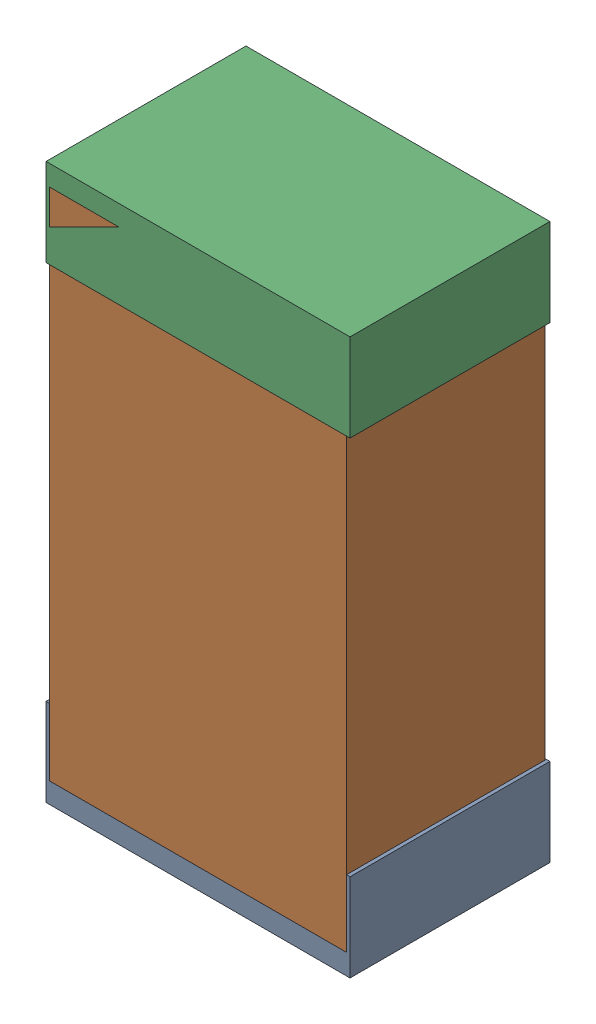
SolidWorks assembly R47Kanaloa_v2.0.0_Motor, configuration Default. Lengths in mm.
Overall size (1.3 2.38 0.85).
6 component instances, 2 part files, 0 mates.
Components (placement in the parent):
- 330415056-1: 330415056 [Default] at (53.34 149.368 -1.9574) size (1.3 0.38 0.85)
  - Extruded_2-1: Extruded_2 [Default] at origin size (1.3 0.38 0.85)
- 334787376-1: 334787376 [Default] at (53.34 150.368 -1.9524) size (1.27 2.2 0.85)
  - Extruded_16-1: Extruded_16 [Default] at origin size (1.27 2.2 0.85)
- 330415056-2: 330415056 [Default] at (53.34 151.368 -1.9574) size (1.3 0.38 0.85)
  - Extruded_2-1: Extruded_2 [Default] at origin size (1.3 0.38 0.85)
